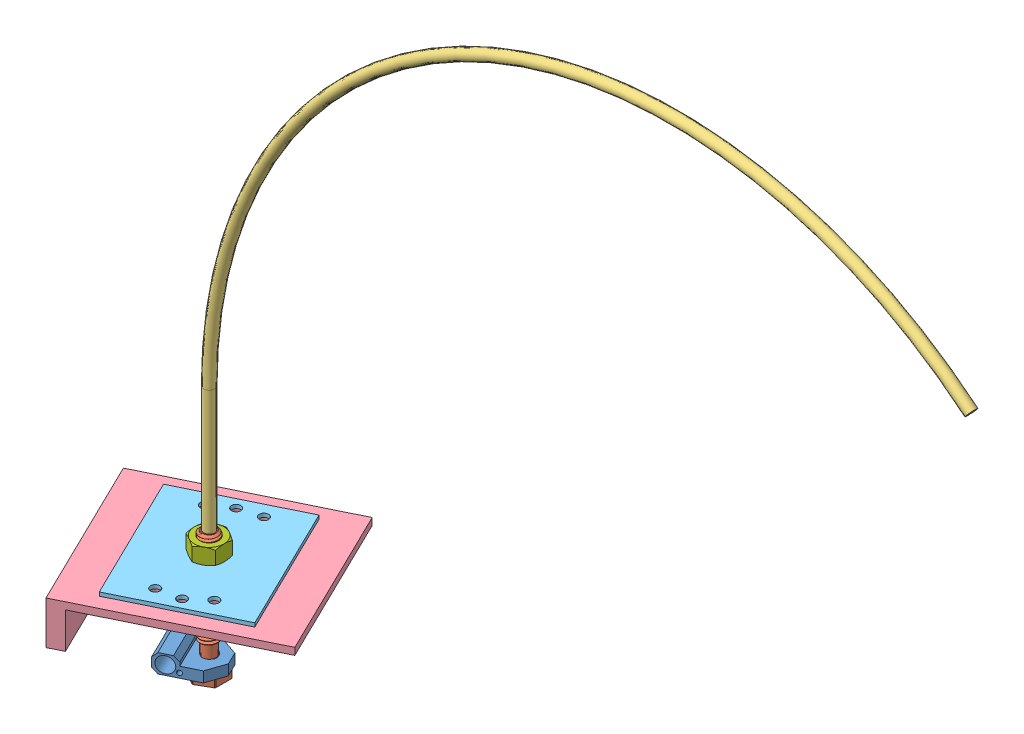
SolidWorks assembly JNozzle, configuration Default. Lengths in mm.
Overall size (369.64 310.39 175.53).
8 component instances, 7 part files, 21 mates.
Components (placement in the parent):
- Heater-1: Heater [Default] at (0 7.6594 0) x (0.898696 0 -0.438573) z (0.438573 0 0.898696) size (22.57 8 18)
- 93190A583-1: 93190A583 [92185A583] at (0 54.4594 0) x (1 0 0) z (0 1 0) size (12.7 14.41 54.84)
- BowdenTube-1: BowdenTube [Default] at (0 7.219 0) x (-0.269173 0 0.963092) z (-0.963092 0 -0.269173) size (92.93 303.17 319.62)
- x-carriage-boltpattern-1: x-carriage-boltpattern [Default] at (-17.9286 44 -33.1667) x (0.898696 0 -0.438573) z (-0.438573 0 -0.898696) size (80 18.5 72.3) (hidden)
- MountPlate^JNozzle-1: MountPlate^JNozzle [Default] at (-17.9286 44 -33.1667) x (0.898696 0 -0.438573) z (0 1 0) size (50 60 1.59) (virtual)
- MountPlate2^JNozzle-1: MountPlate2^JNozzle [Default] at (-17.9286 38 -33.1667) x (-0.898696 0 0.438573) z (0 -1 0) size (59.41 59.41 1.59) (virtual)
- Nut_5-16x18_Al_90670A030-1: Nut_5-16x18_Al_90670A030 [90670A030] at (0 52.3344 0) x (1 0 0) z (0 1 0) size (12.7 14.66 7.78)
- Nut_5-16x18_Al_90670A030-2: Nut_5-16x18_Al_90670A030 [90670A030] at (0 36.4125 0) x (1 0 0) z (0 1 0) size (12.7 14.66 7.78)
Mates (geometry in assembly coordinates):
- Coincident6: coincident anti-aligned: plane of Heater-1 through (-9.8703 3.6594 14.8313) normal (0 -1 0); plane of 93190A583-1 through (6.35 3.6594 -10.9985) normal (0 1 0)
- Concentric2: concentric aligned: cylinder of Heater-1 through (0 3.6594 0) axis (0 1 0) radius 2.75; cylinder of 93190A583-1 through (0 55.8261 0) axis (0 1 0) radius 2.3813
- Coincident7: coincident anti-aligned: plane of 93190A583-1 through (0 54.4594 0) normal (0 0 -1); plane of assembly through (0 0 0) normal (0 0 1)
- Coincident8: coincident aligned: plane of 93190A583-1; plane of assembly through (0 0 0) normal (1 0 0)
- Coincident9: coincident anti-aligned: plane of 93190A583-1 through (0 0 -0.75) normal (0 -1 0); plane of assembly through (0 0 0) normal (0 1 0)
- Coincident10: coincident anti-aligned: circle of 93190A583-1; circle of BowdenTube-1
- Concentric3: concentric anti-aligned: cylinder of 93190A583-1 through (-0.0219 54.2815 0) axis (0 1 0) radius 2.85; cylinder of x-carriage-boltpattern-1 through (-0.0219 44 0) axis (0 -1 0) radius 20.25
- Parallel1: parallel aligned: plane of Heater-1 through (-17.7646 3.6594 -1.3452) normal (-0.898696 0 0.438573); plane of x-carriage-boltpattern-1 through (-51.8242 38 -14.9449) normal (-0.898696 0 0.438573)
- Distance1: distance = 25 mm aligned: plane of x-carriage-boltpattern-1 through (-51.8242 25.5 -14.9449) normal (0 -1 0); plane of 93190A583-1 through (0 0.5 -7.5) normal (0 -1 0)
- InPlace1: in place: plane of ? through (-19.9766 44 50.0863) normal (0 1 0); plane of ? through (0 44 0) normal (0 1 0); moOrthogonalPlaneRef_w of ? through (-19.9766 44 50.0863) normal (0 1 0); unknown of ?; plane of ? through (-19.9766 44 50.0863) normal (0 1 0); unknown of ?; plane of x-carriage-boltpattern-1 through (-20.1154 44 50.0308) normal (0 1 0); unknown of MountPlate^JNozzle-1
- Coincident13: coincident aligned: plane of x-carriage-boltpattern-1; plane of MountPlate^JNozzle-1
- Coincident14: coincident aligned: moOrthogonalPlaneRef_w of x-carriage-boltpattern-1; plane of MountPlate^JNozzle-1
- Coincident15: coincident anti-aligned: moOrthogonalPlaneRef_w of x-carriage-boltpattern-1; plane of MountPlate^JNozzle-1
- InPlace2: in place: plane of x-carriage-boltpattern-1 through (-20.1154 38 50.0308) normal (0 -1 0); plane of ? through (0 38 0) normal (0 -1 0); plane of x-carriage-boltpattern-1 through (-20.1154 38 50.0308) normal (0 -1 0); plane of ? through (0 38 0) normal (0 0 1); plane of x-carriage-boltpattern-1 through (-20.1154 38 50.0308) normal (0 -1 0); unknown of ?; plane of x-carriage-boltpattern-1 through (-20.1154 38 50.0308) normal (0 -1 0); unknown of MountPlate2^JNozzle-1
- Coincident16: coincident aligned: plane of x-carriage-boltpattern-1; plane of MountPlate2^JNozzle-1
- Coincident17: coincident aligned: moOrthogonalPlaneRef_w of x-carriage-boltpattern-1 through (-17.9286 38 -33.1667) normal (-0.438573 0 -0.898696); plane of MountPlate2^JNozzle-1
- Coincident18: coincident anti-aligned: moOrthogonalPlaneRef_w of x-carriage-boltpattern-1 through (-17.9286 38 -33.1667) normal (0.898696 0 -0.438573); plane of MountPlate2^JNozzle-1
- Concentric4: concentric anti-aligned: cylinder of BowdenTube-1 through (0 7.219 0) axis (0 -1 0) radius 2.3813; circle of Nut_5-16x18_Al_90670A030-1
- Coincident11: coincident anti-aligned: plane of MountPlate^JNozzle-1 through (-9.3102 45.5875 37.9252) normal (0 1 0); plane of Nut_5-16x18_Al_90670A030-1 through (6.35 45.5875 -3.6662) normal (0 -1 0)
- Concentric5: concentric anti-aligned: cylinder of BowdenTube-1 through (0 7.219 0) axis (0 -1 0) radius 2.3813; circle of Nut_5-16x18_Al_90670A030-2
- Coincident12: coincident anti-aligned: plane of MountPlate2^JNozzle-1 through (-0.0219 36.4125 0) normal (0 -1 0); plane of Nut_5-16x18_Al_90670A030-2 through (6.35 36.4125 -3.6662) normal (0 1 0)
